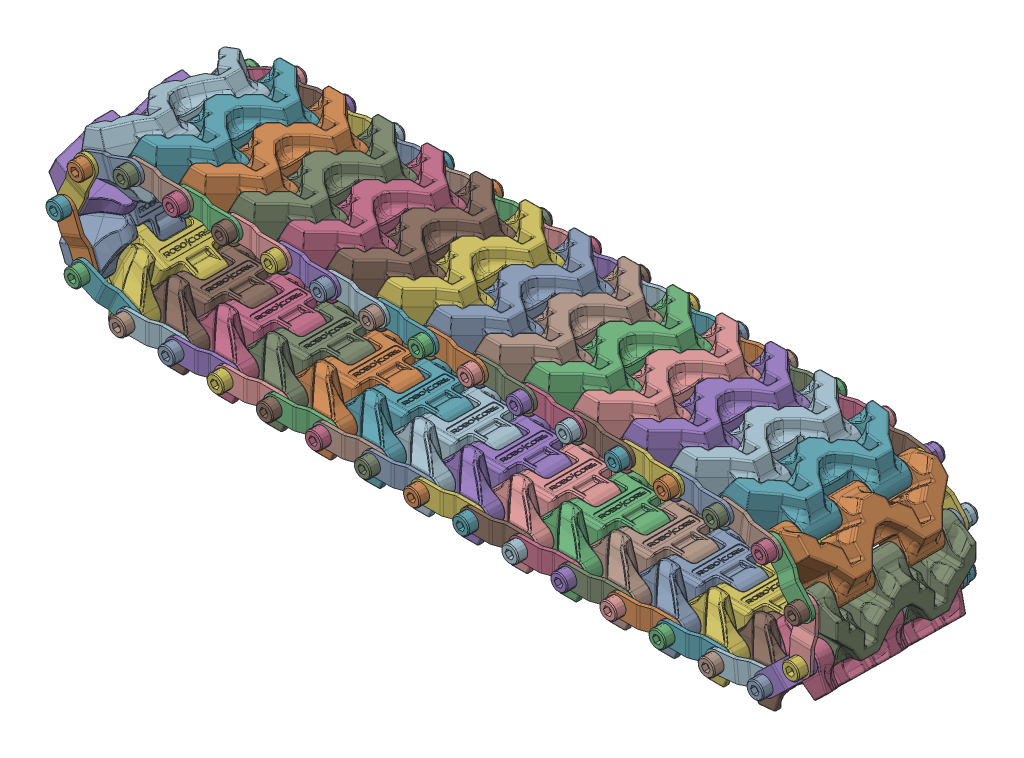
SolidWorks assembly FullTread, configuration Default. Lengths in mm.
Overall size (324.74 77.89 74).
198 component instances, 4 part files, 1 mates.
Components (placement in the parent):
- TRAKTOR_Track_Componentes-V2-5: TRAKTOR_Track_Componentes-V2 [Default] at (-2273.6713 -64.6666 0) x (-0.381584 0.924334 0) z (0 0 -1) size (30.08 26.28 74)
  - Esteira-Traktor-ELEMENTO-V2-25: Esteira-Traktor-ELEMENTO-V2 [Default] at (29.9982 -38.3079 0) x (-0.99994 -0.01097 0) z (0 0 -1) size (29.8 25.95 58)
  - Reforco-tirante-Angulado(Valor predeterminado)-37: Reforco-tirante-Angulado(Valor predeterminado) [Default] at (29.9982 -38.3079 -29.7933) x (-0.99994 -0.01097 0) z (0 0 1) size (28.5 8.5 3)
  - socket head cap screw_am(B18.3.1M - 4 x 0.7 x 70 Hex SHCS -- 20NHX)-19: socket head cap screw_am(B18.3.1M - 4 x 0.7 x 70 Hex SHCS -- 20NHX) [Default] at (19.9988 -38.4176 -35.9962) x (0 0 1) z (-0.823084 0.56792 0) size (74 7 7)
  - prevailing torque nut thin insert_din(DIN EN ISO 10511 - M4 - N)-6: prevailing torque nut thin insert_din(DIN EN ISO 10511 - M4 - N) [Default] at (19.9988 -38.4176 33.9462) x (0.987369 -0.158435 0) z (0 0 1) size (7 8.08 5)
  - Reforco-tirante-Angulado(Valor predeterminado)-51: Reforco-tirante-Angulado(Valor predeterminado) [Default] at (29.9982 -38.3079 31.2029) x (0.99994 0.01097 0) z (0 0 1) size (28.5 8.5 3)
- TRAKTOR_Track_Componentes-V2-61: TRAKTOR_Track_Componentes-V2 [Default] at (-2264.8931 -41.7825 0) x (-0.916884 0.399154 0) z (0 0 -1) size (30.08 26.28 74)
  - Esteira-Traktor-ELEMENTO-V2-25: Esteira-Traktor-ELEMENTO-V2 [Default] at (29.9982 -38.3079 0) x (-0.99994 -0.01097 0) z (0 0 -1) size (29.8 25.95 58)
  - Reforco-tirante-Angulado(Valor predeterminado)-37: Reforco-tirante-Angulado(Valor predeterminado) [Default] at (29.9982 -38.3079 -29.7933) x (-0.99994 -0.01097 0) z (0 0 1) size (28.5 8.5 3)
  - socket head cap screw_am(B18.3.1M - 4 x 0.7 x 70 Hex SHCS -- 20NHX)-19: socket head cap screw_am(B18.3.1M - 4 x 0.7 x 70 Hex SHCS -- 20NHX) [Default] at (19.9988 -38.4176 -35.9962) x (0 0 1) z (-0.823084 0.56792 0) size (74 7 7)
  - prevailing torque nut thin insert_din(DIN EN ISO 10511 - M4 - N)-6: prevailing torque nut thin insert_din(DIN EN ISO 10511 - M4 - N) [Default] at (19.9988 -38.4176 33.9462) x (0.987369 -0.158435 0) z (0 0 1) size (7 8.08 5)
  - Reforco-tirante-Angulado(Valor predeterminado)-51: Reforco-tirante-Angulado(Valor predeterminado) [Default] at (29.9982 -38.3079 31.2029) x (0.99994 0.01097 0) z (0 0 1) size (28.5 8.5 3)
- TRAKTOR_Track_Componentes-V2-62: TRAKTOR_Track_Componentes-V2 [Default] at (-2258.9524 -30.4263 0) x (-0.99995 -0.010047 0) z (0 0 -1) size (30.08 26.28 74)
  - Esteira-Traktor-ELEMENTO-V2-25: Esteira-Traktor-ELEMENTO-V2 [Default] at (29.9982 -38.3079 0) x (-0.99994 -0.01097 0) z (0 0 -1) size (29.8 25.95 58)
  - Reforco-tirante-Angulado(Valor predeterminado)-37: Reforco-tirante-Angulado(Valor predeterminado) [Default] at (29.9982 -38.3079 -29.7933) x (-0.99994 -0.01097 0) z (0 0 1) size (28.5 8.5 3)
  - socket head cap screw_am(B18.3.1M - 4 x 0.7 x 70 Hex SHCS -- 20NHX)-19: socket head cap screw_am(B18.3.1M - 4 x 0.7 x 70 Hex SHCS -- 20NHX) [Default] at (19.9988 -38.4176 -35.9962) x (0 0 1) z (-0.823084 0.56792 0) size (74 7 7)
  - prevailing torque nut thin insert_din(DIN EN ISO 10511 - M4 - N)-6: prevailing torque nut thin insert_din(DIN EN ISO 10511 - M4 - N) [Default] at (19.9988 -38.4176 33.9462) x (0.987369 -0.158435 0) z (0 0 1) size (7 8.08 5)
  - Reforco-tirante-Angulado(Valor predeterminado)-51: Reforco-tirante-Angulado(Valor predeterminado) [Default] at (29.9982 -38.3079 31.2029) x (0.99994 0.01097 0) z (0 0 1) size (28.5 8.5 3)
- TRAKTOR_Track_Componentes-V2-63: TRAKTOR_Track_Componentes-V2 [Default] at (-2238.9881 -30.4082 0) x (-0.99994 -0.01097 0) z (0 0 -1) size (30.08 26.28 74)
  - Esteira-Traktor-ELEMENTO-V2-25: Esteira-Traktor-ELEMENTO-V2 [Default] at (29.9982 -38.3079 0) x (-0.99994 -0.01097 0) z (0 0 -1) size (29.8 25.95 58)
  - Reforco-tirante-Angulado(Valor predeterminado)-37: Reforco-tirante-Angulado(Valor predeterminado) [Default] at (29.9982 -38.3079 -29.7933) x (-0.99994 -0.01097 0) z (0 0 1) size (28.5 8.5 3)
  - socket head cap screw_am(B18.3.1M - 4 x 0.7 x 70 Hex SHCS -- 20NHX)-19: socket head cap screw_am(B18.3.1M - 4 x 0.7 x 70 Hex SHCS -- 20NHX) [Default] at (19.9988 -38.4176 -35.9962) x (0 0 1) z (-0.823084 0.56792 0) size (74 7 7)
  - prevailing torque nut thin insert_din(DIN EN ISO 10511 - M4 - N)-6: prevailing torque nut thin insert_din(DIN EN ISO 10511 - M4 - N) [Default] at (19.9988 -38.4176 33.9462) x (0.987369 -0.158435 0) z (0 0 1) size (7 8.08 5)
  - Reforco-tirante-Angulado(Valor predeterminado)-51: Reforco-tirante-Angulado(Valor predeterminado) [Default] at (29.9982 -38.3079 31.2029) x (0.99994 0.01097 0) z (0 0 1) size (28.5 8.5 3)
- TRAKTOR_Track_Componentes-V2-64: TRAKTOR_Track_Componentes-V2 [Default] at (-2218.9881 -30.4082 0) x (-0.99994 -0.01097 0) z (0 0 -1) size (30.08 26.28 74)
  - Esteira-Traktor-ELEMENTO-V2-25: Esteira-Traktor-ELEMENTO-V2 [Default] at (29.9982 -38.3079 0) x (-0.99994 -0.01097 0) z (0 0 -1) size (29.8 25.95 58)
  - Reforco-tirante-Angulado(Valor predeterminado)-37: Reforco-tirante-Angulado(Valor predeterminado) [Default] at (29.9982 -38.3079 -29.7933) x (-0.99994 -0.01097 0) z (0 0 1) size (28.5 8.5 3)
  - socket head cap screw_am(B18.3.1M - 4 x 0.7 x 70 Hex SHCS -- 20NHX)-19: socket head cap screw_am(B18.3.1M - 4 x 0.7 x 70 Hex SHCS -- 20NHX) [Default] at (19.9988 -38.4176 -35.9962) x (0 0 1) z (-0.823084 0.56792 0) size (74 7 7)
  - prevailing torque nut thin insert_din(DIN EN ISO 10511 - M4 - N)-6: prevailing torque nut thin insert_din(DIN EN ISO 10511 - M4 - N) [Default] at (19.9988 -38.4176 33.9462) x (0.987369 -0.158435 0) z (0 0 1) size (7 8.08 5)
  - Reforco-tirante-Angulado(Valor predeterminado)-51: Reforco-tirante-Angulado(Valor predeterminado) [Default] at (29.9982 -38.3079 31.2029) x (0.99994 0.01097 0) z (0 0 1) size (28.5 8.5 3)
- TRAKTOR_Track_Componentes-V2-65: TRAKTOR_Track_Componentes-V2 [Default] at (-2198.9881 -30.4082 0) x (-0.99994 -0.01097 0) z (0 0 -1) size (30.08 26.28 74)
  - Esteira-Traktor-ELEMENTO-V2-25: Esteira-Traktor-ELEMENTO-V2 [Default] at (29.9982 -38.3079 0) x (-0.99994 -0.01097 0) z (0 0 -1) size (29.8 25.95 58)
  - Reforco-tirante-Angulado(Valor predeterminado)-37: Reforco-tirante-Angulado(Valor predeterminado) [Default] at (29.9982 -38.3079 -29.7933) x (-0.99994 -0.01097 0) z (0 0 1) size (28.5 8.5 3)
  - socket head cap screw_am(B18.3.1M - 4 x 0.7 x 70 Hex SHCS -- 20NHX)-19: socket head cap screw_am(B18.3.1M - 4 x 0.7 x 70 Hex SHCS -- 20NHX) [Default] at (19.9988 -38.4176 -35.9962) x (0 0 1) z (-0.823084 0.56792 0) size (74 7 7)
  - prevailing torque nut thin insert_din(DIN EN ISO 10511 - M4 - N)-6: prevailing torque nut thin insert_din(DIN EN ISO 10511 - M4 - N) [Default] at (19.9988 -38.4176 33.9462) x (0.987369 -0.158435 0) z (0 0 1) size (7 8.08 5)
  - Reforco-tirante-Angulado(Valor predeterminado)-51: Reforco-tirante-Angulado(Valor predeterminado) [Default] at (29.9982 -38.3079 31.2029) x (0.99994 0.01097 0) z (0 0 1) size (28.5 8.5 3)
- TRAKTOR_Track_Componentes-V2-66: TRAKTOR_Track_Componentes-V2 [Default] at (-2178.9881 -30.4082 0) x (-0.99994 -0.01097 0) z (0 0 -1) size (30.08 26.28 74)
  - Esteira-Traktor-ELEMENTO-V2-25: Esteira-Traktor-ELEMENTO-V2 [Default] at (29.9982 -38.3079 0) x (-0.99994 -0.01097 0) z (0 0 -1) size (29.8 25.95 58)
  - Reforco-tirante-Angulado(Valor predeterminado)-37: Reforco-tirante-Angulado(Valor predeterminado) [Default] at (29.9982 -38.3079 -29.7933) x (-0.99994 -0.01097 0) z (0 0 1) size (28.5 8.5 3)
  - socket head cap screw_am(B18.3.1M - 4 x 0.7 x 70 Hex SHCS -- 20NHX)-19: socket head cap screw_am(B18.3.1M - 4 x 0.7 x 70 Hex SHCS -- 20NHX) [Default] at (19.9988 -38.4176 -35.9962) x (0 0 1) z (-0.823084 0.56792 0) size (74 7 7)
  - prevailing torque nut thin insert_din(DIN EN ISO 10511 - M4 - N)-6: prevailing torque nut thin insert_din(DIN EN ISO 10511 - M4 - N) [Default] at (19.9988 -38.4176 33.9462) x (0.987369 -0.158435 0) z (0 0 1) size (7 8.08 5)
  - Reforco-tirante-Angulado(Valor predeterminado)-51: Reforco-tirante-Angulado(Valor predeterminado) [Default] at (29.9982 -38.3079 31.2029) x (0.99994 0.01097 0) z (0 0 1) size (28.5 8.5 3)
- TRAKTOR_Track_Componentes-V2-67: TRAKTOR_Track_Componentes-V2 [Default] at (-2158.9881 -30.4082 0) x (-0.99994 -0.01097 0) z (0 0 -1) size (30.08 26.28 74)
  - Esteira-Traktor-ELEMENTO-V2-25: Esteira-Traktor-ELEMENTO-V2 [Default] at (29.9982 -38.3079 0) x (-0.99994 -0.01097 0) z (0 0 -1) size (29.8 25.95 58)
  - Reforco-tirante-Angulado(Valor predeterminado)-37: Reforco-tirante-Angulado(Valor predeterminado) [Default] at (29.9982 -38.3079 -29.7933) x (-0.99994 -0.01097 0) z (0 0 1) size (28.5 8.5 3)
  - socket head cap screw_am(B18.3.1M - 4 x 0.7 x 70 Hex SHCS -- 20NHX)-19: socket head cap screw_am(B18.3.1M - 4 x 0.7 x 70 Hex SHCS -- 20NHX) [Default] at (19.9988 -38.4176 -35.9962) x (0 0 1) z (-0.823084 0.56792 0) size (74 7 7)
  - prevailing torque nut thin insert_din(DIN EN ISO 10511 - M4 - N)-6: prevailing torque nut thin insert_din(DIN EN ISO 10511 - M4 - N) [Default] at (19.9988 -38.4176 33.9462) x (0.987369 -0.158435 0) z (0 0 1) size (7 8.08 5)
  - Reforco-tirante-Angulado(Valor predeterminado)-51: Reforco-tirante-Angulado(Valor predeterminado) [Default] at (29.9982 -38.3079 31.2029) x (0.99994 0.01097 0) z (0 0 1) size (28.5 8.5 3)
- TRAKTOR_Track_Componentes-V2-68: TRAKTOR_Track_Componentes-V2 [Default] at (-2138.9881 -30.4082 0) x (-0.99994 -0.01097 0) z (0 0 -1) size (30.08 26.28 74)
  - Esteira-Traktor-ELEMENTO-V2-25: Esteira-Traktor-ELEMENTO-V2 [Default] at (29.9982 -38.3079 0) x (-0.99994 -0.01097 0) z (0 0 -1) size (29.8 25.95 58)
  - Reforco-tirante-Angulado(Valor predeterminado)-37: Reforco-tirante-Angulado(Valor predeterminado) [Default] at (29.9982 -38.3079 -29.7933) x (-0.99994 -0.01097 0) z (0 0 1) size (28.5 8.5 3)
  - socket head cap screw_am(B18.3.1M - 4 x 0.7 x 70 Hex SHCS -- 20NHX)-19: socket head cap screw_am(B18.3.1M - 4 x 0.7 x 70 Hex SHCS -- 20NHX) [Default] at (19.9988 -38.4176 -35.9962) x (0 0 1) z (-0.823084 0.56792 0) size (74 7 7)
  - prevailing torque nut thin insert_din(DIN EN ISO 10511 - M4 - N)-6: prevailing torque nut thin insert_din(DIN EN ISO 10511 - M4 - N) [Default] at (19.9988 -38.4176 33.9462) x (0.987369 -0.158435 0) z (0 0 1) size (7 8.08 5)
  - Reforco-tirante-Angulado(Valor predeterminado)-51: Reforco-tirante-Angulado(Valor predeterminado) [Default] at (29.9982 -38.3079 31.2029) x (0.99994 0.01097 0) z (0 0 1) size (28.5 8.5 3)
- TRAKTOR_Track_Componentes-V2-69: TRAKTOR_Track_Componentes-V2 [Default] at (-2118.9881 -30.4082 0) x (-0.99994 -0.01097 0) z (0 0 -1) size (30.08 26.28 74)
  - Esteira-Traktor-ELEMENTO-V2-25: Esteira-Traktor-ELEMENTO-V2 [Default] at (29.9982 -38.3079 0) x (-0.99994 -0.01097 0) z (0 0 -1) size (29.8 25.95 58)
  - Reforco-tirante-Angulado(Valor predeterminado)-37: Reforco-tirante-Angulado(Valor predeterminado) [Default] at (29.9982 -38.3079 -29.7933) x (-0.99994 -0.01097 0) z (0 0 1) size (28.5 8.5 3)
  - socket head cap screw_am(B18.3.1M - 4 x 0.7 x 70 Hex SHCS -- 20NHX)-19: socket head cap screw_am(B18.3.1M - 4 x 0.7 x 70 Hex SHCS -- 20NHX) [Default] at (19.9988 -38.4176 -35.9962) x (0 0 1) z (-0.823084 0.56792 0) size (74 7 7)
  - prevailing torque nut thin insert_din(DIN EN ISO 10511 - M4 - N)-6: prevailing torque nut thin insert_din(DIN EN ISO 10511 - M4 - N) [Default] at (19.9988 -38.4176 33.9462) x (0.987369 -0.158435 0) z (0 0 1) size (7 8.08 5)
  - Reforco-tirante-Angulado(Valor predeterminado)-51: Reforco-tirante-Angulado(Valor predeterminado) [Default] at (29.9982 -38.3079 31.2029) x (0.99994 0.01097 0) z (0 0 1) size (28.5 8.5 3)
- TRAKTOR_Track_Componentes-V2-70: TRAKTOR_Track_Componentes-V2 [Default] at (-2098.9881 -30.4082 0) x (-0.99994 -0.01097 0) z (0 0 -1) size (30.08 26.28 74)
  - Esteira-Traktor-ELEMENTO-V2-25: Esteira-Traktor-ELEMENTO-V2 [Default] at (29.9982 -38.3079 0) x (-0.99994 -0.01097 0) z (0 0 -1) size (29.8 25.95 58)
  - Reforco-tirante-Angulado(Valor predeterminado)-37: Reforco-tirante-Angulado(Valor predeterminado) [Default] at (29.9982 -38.3079 -29.7933) x (-0.99994 -0.01097 0) z (0 0 1) size (28.5 8.5 3)
  - socket head cap screw_am(B18.3.1M - 4 x 0.7 x 70 Hex SHCS -- 20NHX)-19: socket head cap screw_am(B18.3.1M - 4 x 0.7 x 70 Hex SHCS -- 20NHX) [Default] at (19.9988 -38.4176 -35.9962) x (0 0 1) z (-0.823084 0.56792 0) size (74 7 7)
  - prevailing torque nut thin insert_din(DIN EN ISO 10511 - M4 - N)-6: prevailing torque nut thin insert_din(DIN EN ISO 10511 - M4 - N) [Default] at (19.9988 -38.4176 33.9462) x (0.987369 -0.158435 0) z (0 0 1) size (7 8.08 5)
  - Reforco-tirante-Angulado(Valor predeterminado)-51: Reforco-tirante-Angulado(Valor predeterminado) [Default] at (29.9982 -38.3079 31.2029) x (0.99994 0.01097 0) z (0 0 1) size (28.5 8.5 3)
- TRAKTOR_Track_Componentes-V2-71: TRAKTOR_Track_Componentes-V2 [Default] at (-2078.9881 -30.4082 0) x (-0.99994 -0.01097 0) z (0 0 -1) size (30.08 26.28 74)
  - Esteira-Traktor-ELEMENTO-V2-25: Esteira-Traktor-ELEMENTO-V2 [Default] at (29.9982 -38.3079 0) x (-0.99994 -0.01097 0) z (0 0 -1) size (29.8 25.95 58)
  - Reforco-tirante-Angulado(Valor predeterminado)-37: Reforco-tirante-Angulado(Valor predeterminado) [Default] at (29.9982 -38.3079 -29.7933) x (-0.99994 -0.01097 0) z (0 0 1) size (28.5 8.5 3)
  - socket head cap screw_am(B18.3.1M - 4 x 0.7 x 70 Hex SHCS -- 20NHX)-19: socket head cap screw_am(B18.3.1M - 4 x 0.7 x 70 Hex SHCS -- 20NHX) [Default] at (19.9988 -38.4176 -35.9962) x (0 0 1) z (-0.823084 0.56792 0) size (74 7 7)
  - prevailing torque nut thin insert_din(DIN EN ISO 10511 - M4 - N)-6: prevailing torque nut thin insert_din(DIN EN ISO 10511 - M4 - N) [Default] at (19.9988 -38.4176 33.9462) x (0.987369 -0.158435 0) z (0 0 1) size (7 8.08 5)
  - Reforco-tirante-Angulado(Valor predeterminado)-51: Reforco-tirante-Angulado(Valor predeterminado) [Default] at (29.9982 -38.3079 31.2029) x (0.99994 0.01097 0) z (0 0 1) size (28.5 8.5 3)
- TRAKTOR_Track_Componentes-V2-72: TRAKTOR_Track_Componentes-V2 [Default] at (-2058.9881 -30.4082 0) x (-0.99994 -0.01097 0) z (0 0 -1) size (30.08 26.28 74)
  - Esteira-Traktor-ELEMENTO-V2-25: Esteira-Traktor-ELEMENTO-V2 [Default] at (29.9982 -38.3079 0) x (-0.99994 -0.01097 0) z (0 0 -1) size (29.8 25.95 58)
  - Reforco-tirante-Angulado(Valor predeterminado)-37: Reforco-tirante-Angulado(Valor predeterminado) [Default] at (29.9982 -38.3079 -29.7933) x (-0.99994 -0.01097 0) z (0 0 1) size (28.5 8.5 3)
  - socket head cap screw_am(B18.3.1M - 4 x 0.7 x 70 Hex SHCS -- 20NHX)-19: socket head cap screw_am(B18.3.1M - 4 x 0.7 x 70 Hex SHCS -- 20NHX) [Default] at (19.9988 -38.4176 -35.9962) x (0 0 1) z (-0.823084 0.56792 0) size (74 7 7)
  - prevailing torque nut thin insert_din(DIN EN ISO 10511 - M4 - N)-6: prevailing torque nut thin insert_din(DIN EN ISO 10511 - M4 - N) [Default] at (19.9988 -38.4176 33.9462) x (0.987369 -0.158435 0) z (0 0 1) size (7 8.08 5)
  - Reforco-tirante-Angulado(Valor predeterminado)-51: Reforco-tirante-Angulado(Valor predeterminado) [Default] at (29.9982 -38.3079 31.2029) x (0.99994 0.01097 0) z (0 0 1) size (28.5 8.5 3)
- TRAKTOR_Track_Componentes-V2-73: TRAKTOR_Track_Componentes-V2 [Default] at (-2038.9881 -30.4082 0) x (-0.99994 -0.01097 0) z (0 0 -1) size (30.08 26.28 74)
  - Esteira-Traktor-ELEMENTO-V2-25: Esteira-Traktor-ELEMENTO-V2 [Default] at (29.9982 -38.3079 0) x (-0.99994 -0.01097 0) z (0 0 -1) size (29.8 25.95 58)
  - Reforco-tirante-Angulado(Valor predeterminado)-37: Reforco-tirante-Angulado(Valor predeterminado) [Default] at (29.9982 -38.3079 -29.7933) x (-0.99994 -0.01097 0) z (0 0 1) size (28.5 8.5 3)
  - socket head cap screw_am(B18.3.1M - 4 x 0.7 x 70 Hex SHCS -- 20NHX)-19: socket head cap screw_am(B18.3.1M - 4 x 0.7 x 70 Hex SHCS -- 20NHX) [Default] at (19.9988 -38.4176 -35.9962) x (0 0 1) z (-0.823084 0.56792 0) size (74 7 7)
  - prevailing torque nut thin insert_din(DIN EN ISO 10511 - M4 - N)-6: prevailing torque nut thin insert_din(DIN EN ISO 10511 - M4 - N) [Default] at (19.9988 -38.4176 33.9462) x (0.987369 -0.158435 0) z (0 0 1) size (7 8.08 5)
  - Reforco-tirante-Angulado(Valor predeterminado)-51: Reforco-tirante-Angulado(Valor predeterminado) [Default] at (29.9982 -38.3079 31.2029) x (0.99994 0.01097 0) z (0 0 1) size (28.5 8.5 3)
- TRAKTOR_Track_Componentes-V2-74: TRAKTOR_Track_Componentes-V2 [Default] at (-2022.9285 -26.7462 0) x (-0.994144 -0.108059 0) z (0 0 -1) size (30.08 26.28 74)
  - Esteira-Traktor-ELEMENTO-V2-25: Esteira-Traktor-ELEMENTO-V2 [Default] at (29.9982 -38.3079 0) x (-0.99994 -0.01097 0) z (0 0 -1) size (29.8 25.95 58)
  - Reforco-tirante-Angulado(Valor predeterminado)-37: Reforco-tirante-Angulado(Valor predeterminado) [Default] at (29.9982 -38.3079 -29.7933) x (-0.99994 -0.01097 0) z (0 0 1) size (28.5 8.5 3)
  - socket head cap screw_am(B18.3.1M - 4 x 0.7 x 70 Hex SHCS -- 20NHX)-19: socket head cap screw_am(B18.3.1M - 4 x 0.7 x 70 Hex SHCS -- 20NHX) [Default] at (19.9988 -38.4176 -35.9962) x (0 0 1) z (-0.823084 0.56792 0) size (74 7 7)
  - prevailing torque nut thin insert_din(DIN EN ISO 10511 - M4 - N)-6: prevailing torque nut thin insert_din(DIN EN ISO 10511 - M4 - N) [Default] at (19.9988 -38.4176 33.9462) x (0.987369 -0.158435 0) z (0 0 1) size (7 8.08 5)
  - Reforco-tirante-Angulado(Valor predeterminado)-51: Reforco-tirante-Angulado(Valor predeterminado) [Default] at (29.9982 -38.3079 31.2029) x (0.99994 0.01097 0) z (0 0 1) size (28.5 8.5 3)
- TRAKTOR_Track_Componentes-V2-75: TRAKTOR_Track_Componentes-V2 [Default] at (-2037.0538 -11.8158 0) x (-0.711348 -0.70284 0) z (0 0 -1) size (30.08 26.28 74)
  - Esteira-Traktor-ELEMENTO-V2-25: Esteira-Traktor-ELEMENTO-V2 [Default] at (29.9982 -38.3079 0) x (-0.99994 -0.01097 0) z (0 0 -1) size (29.8 25.95 58)
  - Reforco-tirante-Angulado(Valor predeterminado)-37: Reforco-tirante-Angulado(Valor predeterminado) [Default] at (29.9982 -38.3079 -29.7933) x (-0.99994 -0.01097 0) z (0 0 1) size (28.5 8.5 3)
  - socket head cap screw_am(B18.3.1M - 4 x 0.7 x 70 Hex SHCS -- 20NHX)-19: socket head cap screw_am(B18.3.1M - 4 x 0.7 x 70 Hex SHCS -- 20NHX) [Default] at (19.9988 -38.4176 -35.9962) x (0 0 1) z (-0.823084 0.56792 0) size (74 7 7)
  - prevailing torque nut thin insert_din(DIN EN ISO 10511 - M4 - N)-6: prevailing torque nut thin insert_din(DIN EN ISO 10511 - M4 - N) [Default] at (19.9988 -38.4176 33.9462) x (0.987369 -0.158435 0) z (0 0 1) size (7 8.08 5)
  - Reforco-tirante-Angulado(Valor predeterminado)-51: Reforco-tirante-Angulado(Valor predeterminado) [Default] at (29.9982 -38.3079 31.2029) x (0.99994 0.01097 0) z (0 0 1) size (28.5 8.5 3)
- TRAKTOR_Track_Componentes-V2-76: TRAKTOR_Track_Componentes-V2 [Default] at (-2061.5581 -12.3449 0) x (-0.02272 -0.999742 0) z (0 0 -1) size (30.08 26.28 74)
  - Esteira-Traktor-ELEMENTO-V2-25: Esteira-Traktor-ELEMENTO-V2 [Default] at (29.9982 -38.3079 0) x (-0.99994 -0.01097 0) z (0 0 -1) size (29.8 25.95 58)
  - Reforco-tirante-Angulado(Valor predeterminado)-37: Reforco-tirante-Angulado(Valor predeterminado) [Default] at (29.9982 -38.3079 -29.7933) x (-0.99994 -0.01097 0) z (0 0 1) size (28.5 8.5 3)
  - socket head cap screw_am(B18.3.1M - 4 x 0.7 x 70 Hex SHCS -- 20NHX)-19: socket head cap screw_am(B18.3.1M - 4 x 0.7 x 70 Hex SHCS -- 20NHX) [Default] at (19.9988 -38.4176 -35.9962) x (0 0 1) z (-0.823084 0.56792 0) size (74 7 7)
  - prevailing torque nut thin insert_din(DIN EN ISO 10511 - M4 - N)-6: prevailing torque nut thin insert_din(DIN EN ISO 10511 - M4 - N) [Default] at (19.9988 -38.4176 33.9462) x (0.987369 -0.158435 0) z (0 0 1) size (7 8.08 5)
  - Reforco-tirante-Angulado(Valor predeterminado)-51: Reforco-tirante-Angulado(Valor predeterminado) [Default] at (29.9982 -38.3079 31.2029) x (0.99994 0.01097 0) z (0 0 1) size (28.5 8.5 3)
- TRAKTOR_Track_Componentes-V2-77: TRAKTOR_Track_Componentes-V2 [Default] at (-2078.8044 -29.7606 0) x (0.678685 -0.734429 0) z (0 0 -1) size (30.08 26.28 74)
  - Esteira-Traktor-ELEMENTO-V2-25: Esteira-Traktor-ELEMENTO-V2 [Default] at (29.9982 -38.3079 0) x (-0.99994 -0.01097 0) z (0 0 -1) size (29.8 25.95 58)
  - Reforco-tirante-Angulado(Valor predeterminado)-37: Reforco-tirante-Angulado(Valor predeterminado) [Default] at (29.9982 -38.3079 -29.7933) x (-0.99994 -0.01097 0) z (0 0 1) size (28.5 8.5 3)
  - socket head cap screw_am(B18.3.1M - 4 x 0.7 x 70 Hex SHCS -- 20NHX)-19: socket head cap screw_am(B18.3.1M - 4 x 0.7 x 70 Hex SHCS -- 20NHX) [Default] at (19.9988 -38.4176 -35.9962) x (0 0 1) z (-0.823084 0.56792 0) size (74 7 7)
  - prevailing torque nut thin insert_din(DIN EN ISO 10511 - M4 - N)-6: prevailing torque nut thin insert_din(DIN EN ISO 10511 - M4 - N) [Default] at (19.9988 -38.4176 33.9462) x (0.987369 -0.158435 0) z (0 0 1) size (7 8.08 5)
  - Reforco-tirante-Angulado(Valor predeterminado)-51: Reforco-tirante-Angulado(Valor predeterminado) [Default] at (29.9982 -38.3079 31.2029) x (0.99994 0.01097 0) z (0 0 1) size (28.5 8.5 3)
- TRAKTOR_Track_Componentes-V2-78: TRAKTOR_Track_Componentes-V2 [Default] at (-2081.3993 -51.376 0) x (0.992442 -0.122716 0) z (0 0 -1) size (30.08 26.28 74)
  - Esteira-Traktor-ELEMENTO-V2-25: Esteira-Traktor-ELEMENTO-V2 [Default] at (29.9982 -38.3079 0) x (-0.99994 -0.01097 0) z (0 0 -1) size (29.8 25.95 58)
  - Reforco-tirante-Angulado(Valor predeterminado)-37: Reforco-tirante-Angulado(Valor predeterminado) [Default] at (29.9982 -38.3079 -29.7933) x (-0.99994 -0.01097 0) z (0 0 1) size (28.5 8.5 3)
  - socket head cap screw_am(B18.3.1M - 4 x 0.7 x 70 Hex SHCS -- 20NHX)-19: socket head cap screw_am(B18.3.1M - 4 x 0.7 x 70 Hex SHCS -- 20NHX) [Default] at (19.9988 -38.4176 -35.9962) x (0 0 1) z (-0.823084 0.56792 0) size (74 7 7)
  - prevailing torque nut thin insert_din(DIN EN ISO 10511 - M4 - N)-6: prevailing torque nut thin insert_din(DIN EN ISO 10511 - M4 - N) [Default] at (19.9988 -38.4176 33.9462) x (0.987369 -0.158435 0) z (0 0 1) size (7 8.08 5)
  - Reforco-tirante-Angulado(Valor predeterminado)-51: Reforco-tirante-Angulado(Valor predeterminado) [Default] at (29.9982 -38.3079 31.2029) x (0.99994 0.01097 0) z (0 0 1) size (28.5 8.5 3)
- TRAKTOR_Track_Componentes-V2-79: TRAKTOR_Track_Componentes-V2 [Default] at (-2096.4134 -54.3376 0) x (0.99994 0.01097 0) z (0 0 -1) size (30.08 26.28 74)
  - Esteira-Traktor-ELEMENTO-V2-25: Esteira-Traktor-ELEMENTO-V2 [Default] at (29.9982 -38.3079 0) x (-0.99994 -0.01097 0) z (0 0 -1) size (29.8 25.95 58)
  - Reforco-tirante-Angulado(Valor predeterminado)-37: Reforco-tirante-Angulado(Valor predeterminado) [Default] at (29.9982 -38.3079 -29.7933) x (-0.99994 -0.01097 0) z (0 0 1) size (28.5 8.5 3)
  - socket head cap screw_am(B18.3.1M - 4 x 0.7 x 70 Hex SHCS -- 20NHX)-19: socket head cap screw_am(B18.3.1M - 4 x 0.7 x 70 Hex SHCS -- 20NHX) [Default] at (19.9988 -38.4176 -35.9962) x (0 0 1) z (-0.823084 0.56792 0) size (74 7 7)
  - prevailing torque nut thin insert_din(DIN EN ISO 10511 - M4 - N)-6: prevailing torque nut thin insert_din(DIN EN ISO 10511 - M4 - N) [Default] at (19.9988 -38.4176 33.9462) x (0.987369 -0.158435 0) z (0 0 1) size (7 8.08 5)
  - Reforco-tirante-Angulado(Valor predeterminado)-51: Reforco-tirante-Angulado(Valor predeterminado) [Default] at (29.9982 -38.3079 31.2029) x (0.99994 0.01097 0) z (0 0 1) size (28.5 8.5 3)
- TRAKTOR_Track_Componentes-V2-80: TRAKTOR_Track_Componentes-V2 [Default] at (-2116.4134 -54.3376 0) x (0.99994 0.01097 0) z (0 0 -1) size (30.08 26.28 74)
  - Esteira-Traktor-ELEMENTO-V2-25: Esteira-Traktor-ELEMENTO-V2 [Default] at (29.9982 -38.3079 0) x (-0.99994 -0.01097 0) z (0 0 -1) size (29.8 25.95 58)
  - Reforco-tirante-Angulado(Valor predeterminado)-37: Reforco-tirante-Angulado(Valor predeterminado) [Default] at (29.9982 -38.3079 -29.7933) x (-0.99994 -0.01097 0) z (0 0 1) size (28.5 8.5 3)
  - socket head cap screw_am(B18.3.1M - 4 x 0.7 x 70 Hex SHCS -- 20NHX)-19: socket head cap screw_am(B18.3.1M - 4 x 0.7 x 70 Hex SHCS -- 20NHX) [Default] at (19.9988 -38.4176 -35.9962) x (0 0 1) z (-0.823084 0.56792 0) size (74 7 7)
  - prevailing torque nut thin insert_din(DIN EN ISO 10511 - M4 - N)-6: prevailing torque nut thin insert_din(DIN EN ISO 10511 - M4 - N) [Default] at (19.9988 -38.4176 33.9462) x (0.987369 -0.158435 0) z (0 0 1) size (7 8.08 5)
  - Reforco-tirante-Angulado(Valor predeterminado)-51: Reforco-tirante-Angulado(Valor predeterminado) [Default] at (29.9982 -38.3079 31.2029) x (0.99994 0.01097 0) z (0 0 1) size (28.5 8.5 3)
- TRAKTOR_Track_Componentes-V2-81: TRAKTOR_Track_Componentes-V2 [Default] at (-2136.4134 -54.3376 0) x (0.99994 0.01097 0) z (0 0 -1) size (30.08 26.28 74)
  - Esteira-Traktor-ELEMENTO-V2-25: Esteira-Traktor-ELEMENTO-V2 [Default] at (29.9982 -38.3079 0) x (-0.99994 -0.01097 0) z (0 0 -1) size (29.8 25.95 58)
  - Reforco-tirante-Angulado(Valor predeterminado)-37: Reforco-tirante-Angulado(Valor predeterminado) [Default] at (29.9982 -38.3079 -29.7933) x (-0.99994 -0.01097 0) z (0 0 1) size (28.5 8.5 3)
  - socket head cap screw_am(B18.3.1M - 4 x 0.7 x 70 Hex SHCS -- 20NHX)-19: socket head cap screw_am(B18.3.1M - 4 x 0.7 x 70 Hex SHCS -- 20NHX) [Default] at (19.9988 -38.4176 -35.9962) x (0 0 1) z (-0.823084 0.56792 0) size (74 7 7)
  - prevailing torque nut thin insert_din(DIN EN ISO 10511 - M4 - N)-6: prevailing torque nut thin insert_din(DIN EN ISO 10511 - M4 - N) [Default] at (19.9988 -38.4176 33.9462) x (0.987369 -0.158435 0) z (0 0 1) size (7 8.08 5)
  - Reforco-tirante-Angulado(Valor predeterminado)-51: Reforco-tirante-Angulado(Valor predeterminado) [Default] at (29.9982 -38.3079 31.2029) x (0.99994 0.01097 0) z (0 0 1) size (28.5 8.5 3)
- TRAKTOR_Track_Componentes-V2-82: TRAKTOR_Track_Componentes-V2 [Default] at (-2156.4134 -54.3376 0) x (0.99994 0.01097 0) z (0 0 -1) size (30.08 26.28 74)
  - Esteira-Traktor-ELEMENTO-V2-25: Esteira-Traktor-ELEMENTO-V2 [Default] at (29.9982 -38.3079 0) x (-0.99994 -0.01097 0) z (0 0 -1) size (29.8 25.95 58)
  - Reforco-tirante-Angulado(Valor predeterminado)-37: Reforco-tirante-Angulado(Valor predeterminado) [Default] at (29.9982 -38.3079 -29.7933) x (-0.99994 -0.01097 0) z (0 0 1) size (28.5 8.5 3)
  - socket head cap screw_am(B18.3.1M - 4 x 0.7 x 70 Hex SHCS -- 20NHX)-19: socket head cap screw_am(B18.3.1M - 4 x 0.7 x 70 Hex SHCS -- 20NHX) [Default] at (19.9988 -38.4176 -35.9962) x (0 0 1) z (-0.823084 0.56792 0) size (74 7 7)
  - prevailing torque nut thin insert_din(DIN EN ISO 10511 - M4 - N)-6: prevailing torque nut thin insert_din(DIN EN ISO 10511 - M4 - N) [Default] at (19.9988 -38.4176 33.9462) x (0.987369 -0.158435 0) z (0 0 1) size (7 8.08 5)
  - Reforco-tirante-Angulado(Valor predeterminado)-51: Reforco-tirante-Angulado(Valor predeterminado) [Default] at (29.9982 -38.3079 31.2029) x (0.99994 0.01097 0) z (0 0 1) size (28.5 8.5 3)
- TRAKTOR_Track_Componentes-V2-83: TRAKTOR_Track_Componentes-V2 [Default] at (-2176.4134 -54.3376 0) x (0.99994 0.01097 0) z (0 0 -1) size (30.08 26.28 74)
  - Esteira-Traktor-ELEMENTO-V2-25: Esteira-Traktor-ELEMENTO-V2 [Default] at (29.9982 -38.3079 0) x (-0.99994 -0.01097 0) z (0 0 -1) size (29.8 25.95 58)
  - Reforco-tirante-Angulado(Valor predeterminado)-37: Reforco-tirante-Angulado(Valor predeterminado) [Default] at (29.9982 -38.3079 -29.7933) x (-0.99994 -0.01097 0) z (0 0 1) size (28.5 8.5 3)
  - socket head cap screw_am(B18.3.1M - 4 x 0.7 x 70 Hex SHCS -- 20NHX)-19: socket head cap screw_am(B18.3.1M - 4 x 0.7 x 70 Hex SHCS -- 20NHX) [Default] at (19.9988 -38.4176 -35.9962) x (0 0 1) z (-0.823084 0.56792 0) size (74 7 7)
  - prevailing torque nut thin insert_din(DIN EN ISO 10511 - M4 - N)-6: prevailing torque nut thin insert_din(DIN EN ISO 10511 - M4 - N) [Default] at (19.9988 -38.4176 33.9462) x (0.987369 -0.158435 0) z (0 0 1) size (7 8.08 5)
  - Reforco-tirante-Angulado(Valor predeterminado)-51: Reforco-tirante-Angulado(Valor predeterminado) [Default] at (29.9982 -38.3079 31.2029) x (0.99994 0.01097 0) z (0 0 1) size (28.5 8.5 3)
- TRAKTOR_Track_Componentes-V2-84: TRAKTOR_Track_Componentes-V2 [Default] at (-2196.4134 -54.3376 0) x (0.99994 0.01097 0) z (0 0 -1) size (30.08 26.28 74)
  - Esteira-Traktor-ELEMENTO-V2-25: Esteira-Traktor-ELEMENTO-V2 [Default] at (29.9982 -38.3079 0) x (-0.99994 -0.01097 0) z (0 0 -1) size (29.8 25.95 58)
  - Reforco-tirante-Angulado(Valor predeterminado)-37: Reforco-tirante-Angulado(Valor predeterminado) [Default] at (29.9982 -38.3079 -29.7933) x (-0.99994 -0.01097 0) z (0 0 1) size (28.5 8.5 3)
  - socket head cap screw_am(B18.3.1M - 4 x 0.7 x 70 Hex SHCS -- 20NHX)-19: socket head cap screw_am(B18.3.1M - 4 x 0.7 x 70 Hex SHCS -- 20NHX) [Default] at (19.9988 -38.4176 -35.9962) x (0 0 1) z (-0.823084 0.56792 0) size (74 7 7)
  - prevailing torque nut thin insert_din(DIN EN ISO 10511 - M4 - N)-6: prevailing torque nut thin insert_din(DIN EN ISO 10511 - M4 - N) [Default] at (19.9988 -38.4176 33.9462) x (0.987369 -0.158435 0) z (0 0 1) size (7 8.08 5)
  - Reforco-tirante-Angulado(Valor predeterminado)-51: Reforco-tirante-Angulado(Valor predeterminado) [Default] at (29.9982 -38.3079 31.2029) x (0.99994 0.01097 0) z (0 0 1) size (28.5 8.5 3)
- TRAKTOR_Track_Componentes-V2-85: TRAKTOR_Track_Componentes-V2 [Default] at (-2216.4134 -54.3376 0) x (0.99994 0.01097 0) z (0 0 -1) size (30.08 26.28 74)
  - Esteira-Traktor-ELEMENTO-V2-25: Esteira-Traktor-ELEMENTO-V2 [Default] at (29.9982 -38.3079 0) x (-0.99994 -0.01097 0) z (0 0 -1) size (29.8 25.95 58)
  - Reforco-tirante-Angulado(Valor predeterminado)-37: Reforco-tirante-Angulado(Valor predeterminado) [Default] at (29.9982 -38.3079 -29.7933) x (-0.99994 -0.01097 0) z (0 0 1) size (28.5 8.5 3)
  - socket head cap screw_am(B18.3.1M - 4 x 0.7 x 70 Hex SHCS -- 20NHX)-19: socket head cap screw_am(B18.3.1M - 4 x 0.7 x 70 Hex SHCS -- 20NHX) [Default] at (19.9988 -38.4176 -35.9962) x (0 0 1) z (-0.823084 0.56792 0) size (74 7 7)
  - prevailing torque nut thin insert_din(DIN EN ISO 10511 - M4 - N)-6: prevailing torque nut thin insert_din(DIN EN ISO 10511 - M4 - N) [Default] at (19.9988 -38.4176 33.9462) x (0.987369 -0.158435 0) z (0 0 1) size (7 8.08 5)
  - Reforco-tirante-Angulado(Valor predeterminado)-51: Reforco-tirante-Angulado(Valor predeterminado) [Default] at (29.9982 -38.3079 31.2029) x (0.99994 0.01097 0) z (0 0 1) size (28.5 8.5 3)
- TRAKTOR_Track_Componentes-V2-111: TRAKTOR_Track_Componentes-V2 [Default] at (-2236.4134 -54.3376 0) x (0.99994 0.01097 0) z (0 0 -1) size (30.08 26.28 74)
  - Esteira-Traktor-ELEMENTO-V2-25: Esteira-Traktor-ELEMENTO-V2 [Default] at (29.9982 -38.3079 0) x (-0.99994 -0.01097 0) z (0 0 -1) size (29.8 25.95 58)
  - Reforco-tirante-Angulado(Valor predeterminado)-37: Reforco-tirante-Angulado(Valor predeterminado) [Default] at (29.9982 -38.3079 -29.7933) x (-0.99994 -0.01097 0) z (0 0 1) size (28.5 8.5 3)
  - socket head cap screw_am(B18.3.1M - 4 x 0.7 x 70 Hex SHCS -- 20NHX)-19: socket head cap screw_am(B18.3.1M - 4 x 0.7 x 70 Hex SHCS -- 20NHX) [Default] at (19.9988 -38.4176 -35.9962) x (0 0 1) z (-0.823084 0.56792 0) size (74 7 7)
  - prevailing torque nut thin insert_din(DIN EN ISO 10511 - M4 - N)-6: prevailing torque nut thin insert_din(DIN EN ISO 10511 - M4 - N) [Default] at (19.9988 -38.4176 33.9462) x (0.987369 -0.158435 0) z (0 0 1) size (7 8.08 5)
  - Reforco-tirante-Angulado(Valor predeterminado)-51: Reforco-tirante-Angulado(Valor predeterminado) [Default] at (29.9982 -38.3079 31.2029) x (0.99994 0.01097 0) z (0 0 1) size (28.5 8.5 3)
- TRAKTOR_Track_Componentes-V2-112: TRAKTOR_Track_Componentes-V2 [Default] at (-2256.4134 -54.3376 0) x (0.99994 0.01097 0) z (0 0 -1) size (30.08 26.28 74)
  - Esteira-Traktor-ELEMENTO-V2-25: Esteira-Traktor-ELEMENTO-V2 [Default] at (29.9982 -38.3079 0) x (-0.99994 -0.01097 0) z (0 0 -1) size (29.8 25.95 58)
  - Reforco-tirante-Angulado(Valor predeterminado)-37: Reforco-tirante-Angulado(Valor predeterminado) [Default] at (29.9982 -38.3079 -29.7933) x (-0.99994 -0.01097 0) z (0 0 1) size (28.5 8.5 3)
  - socket head cap screw_am(B18.3.1M - 4 x 0.7 x 70 Hex SHCS -- 20NHX)-19: socket head cap screw_am(B18.3.1M - 4 x 0.7 x 70 Hex SHCS -- 20NHX) [Default] at (19.9988 -38.4176 -35.9962) x (0 0 1) z (-0.823084 0.56792 0) size (74 7 7)
  - prevailing torque nut thin insert_din(DIN EN ISO 10511 - M4 - N)-6: prevailing torque nut thin insert_din(DIN EN ISO 10511 - M4 - N) [Default] at (19.9988 -38.4176 33.9462) x (0.987369 -0.158435 0) z (0 0 1) size (7 8.08 5)
  - Reforco-tirante-Angulado(Valor predeterminado)-51: Reforco-tirante-Angulado(Valor predeterminado) [Default] at (29.9982 -38.3079 31.2029) x (0.99994 0.01097 0) z (0 0 1) size (28.5 8.5 3)
- TRAKTOR_Track_Componentes-V2-113: TRAKTOR_Track_Componentes-V2 [Default] at (-2276.4134 -54.3376 0) x (0.99994 0.01097 0) z (0 0 -1) size (30.08 26.28 74)
  - Esteira-Traktor-ELEMENTO-V2-25: Esteira-Traktor-ELEMENTO-V2 [Default] at (29.9982 -38.3079 0) x (-0.99994 -0.01097 0) z (0 0 -1) size (29.8 25.95 58)
  - Reforco-tirante-Angulado(Valor predeterminado)-37: Reforco-tirante-Angulado(Valor predeterminado) [Default] at (29.9982 -38.3079 -29.7933) x (-0.99994 -0.01097 0) z (0 0 1) size (28.5 8.5 3)
  - socket head cap screw_am(B18.3.1M - 4 x 0.7 x 70 Hex SHCS -- 20NHX)-19: socket head cap screw_am(B18.3.1M - 4 x 0.7 x 70 Hex SHCS -- 20NHX) [Default] at (19.9988 -38.4176 -35.9962) x (0 0 1) z (-0.823084 0.56792 0) size (74 7 7)
  - prevailing torque nut thin insert_din(DIN EN ISO 10511 - M4 - N)-6: prevailing torque nut thin insert_din(DIN EN ISO 10511 - M4 - N) [Default] at (19.9988 -38.4176 33.9462) x (0.987369 -0.158435 0) z (0 0 1) size (7 8.08 5)
  - Reforco-tirante-Angulado(Valor predeterminado)-51: Reforco-tirante-Angulado(Valor predeterminado) [Default] at (29.9982 -38.3079 31.2029) x (0.99994 0.01097 0) z (0 0 1) size (28.5 8.5 3)
- TRAKTOR_Track_Componentes-V2-114: TRAKTOR_Track_Componentes-V2 [Default] at (-2296.4134 -54.3376 0) x (0.99994 0.01097 0) z (0 0 -1) size (30.08 26.28 74)
  - Esteira-Traktor-ELEMENTO-V2-25: Esteira-Traktor-ELEMENTO-V2 [Default] at (29.9982 -38.3079 0) x (-0.99994 -0.01097 0) z (0 0 -1) size (29.8 25.95 58)
  - Reforco-tirante-Angulado(Valor predeterminado)-37: Reforco-tirante-Angulado(Valor predeterminado) [Default] at (29.9982 -38.3079 -29.7933) x (-0.99994 -0.01097 0) z (0 0 1) size (28.5 8.5 3)
  - socket head cap screw_am(B18.3.1M - 4 x 0.7 x 70 Hex SHCS -- 20NHX)-19: socket head cap screw_am(B18.3.1M - 4 x 0.7 x 70 Hex SHCS -- 20NHX) [Default] at (19.9988 -38.4176 -35.9962) x (0 0 1) z (-0.823084 0.56792 0) size (74 7 7)
  - prevailing torque nut thin insert_din(DIN EN ISO 10511 - M4 - N)-6: prevailing torque nut thin insert_din(DIN EN ISO 10511 - M4 - N) [Default] at (19.9988 -38.4176 33.9462) x (0.987369 -0.158435 0) z (0 0 1) size (7 8.08 5)
  - Reforco-tirante-Angulado(Valor predeterminado)-51: Reforco-tirante-Angulado(Valor predeterminado) [Default] at (29.9982 -38.3079 31.2029) x (0.99994 0.01097 0) z (0 0 1) size (28.5 8.5 3)
- TRAKTOR_Track_Componentes-V2-115: TRAKTOR_Track_Componentes-V2 [Default] at (-2316.4134 -54.3376 0) x (0.99994 0.01097 0) z (0 0 -1) size (30.08 26.28 74)
  - Esteira-Traktor-ELEMENTO-V2-25: Esteira-Traktor-ELEMENTO-V2 [Default] at (29.9982 -38.3079 0) x (-0.99994 -0.01097 0) z (0 0 -1) size (29.8 25.95 58)
  - Reforco-tirante-Angulado(Valor predeterminado)-37: Reforco-tirante-Angulado(Valor predeterminado) [Default] at (29.9982 -38.3079 -29.7933) x (-0.99994 -0.01097 0) z (0 0 1) size (28.5 8.5 3)
  - socket head cap screw_am(B18.3.1M - 4 x 0.7 x 70 Hex SHCS -- 20NHX)-19: socket head cap screw_am(B18.3.1M - 4 x 0.7 x 70 Hex SHCS -- 20NHX) [Default] at (19.9988 -38.4176 -35.9962) x (0 0 1) z (-0.823084 0.56792 0) size (74 7 7)
  - prevailing torque nut thin insert_din(DIN EN ISO 10511 - M4 - N)-6: prevailing torque nut thin insert_din(DIN EN ISO 10511 - M4 - N) [Default] at (19.9988 -38.4176 33.9462) x (0.987369 -0.158435 0) z (0 0 1) size (7 8.08 5)
  - Reforco-tirante-Angulado(Valor predeterminado)-51: Reforco-tirante-Angulado(Valor predeterminado) [Default] at (29.9982 -38.3079 31.2029) x (0.99994 0.01097 0) z (0 0 1) size (28.5 8.5 3)
- TRAKTOR_Track_Componentes-V2-116: TRAKTOR_Track_Componentes-V2 [Default] at (-2320.4065 -65.7369 0) x (0.932986 0.359912 0) z (0 0 -1) size (30.08 26.28 74)
  - Esteira-Traktor-ELEMENTO-V2-25: Esteira-Traktor-ELEMENTO-V2 [Default] at (29.9982 -38.3079 0) x (-0.99994 -0.01097 0) z (0 0 -1) size (29.8 25.95 58)
  - Reforco-tirante-Angulado(Valor predeterminado)-37: Reforco-tirante-Angulado(Valor predeterminado) [Default] at (29.9982 -38.3079 -29.7933) x (-0.99994 -0.01097 0) z (0 0 1) size (28.5 8.5 3)
  - socket head cap screw_am(B18.3.1M - 4 x 0.7 x 70 Hex SHCS -- 20NHX)-19: socket head cap screw_am(B18.3.1M - 4 x 0.7 x 70 Hex SHCS -- 20NHX) [Default] at (19.9988 -38.4176 -35.9962) x (0 0 1) z (-0.823084 0.56792 0) size (74 7 7)
  - prevailing torque nut thin insert_din(DIN EN ISO 10511 - M4 - N)-6: prevailing torque nut thin insert_din(DIN EN ISO 10511 - M4 - N) [Default] at (19.9988 -38.4176 33.9462) x (0.987369 -0.158435 0) z (0 0 1) size (7 8.08 5)
  - Reforco-tirante-Angulado(Valor predeterminado)-51: Reforco-tirante-Angulado(Valor predeterminado) [Default] at (29.9982 -38.3079 31.2029) x (0.99994 0.01097 0) z (0 0 1) size (28.5 8.5 3)
- TRAKTOR_Track_Componentes-V2-117: TRAKTOR_Track_Componentes-V2 [Default] at (-2297.762 -75.0564 0) x (0.420936 0.907091 0) z (0 0 -1) size (30.08 26.28 74)
  - Esteira-Traktor-ELEMENTO-V2-25: Esteira-Traktor-ELEMENTO-V2 [Default] at (29.9982 -38.3079 0) x (-0.99994 -0.01097 0) z (0 0 -1) size (29.8 25.95 58)
  - Reforco-tirante-Angulado(Valor predeterminado)-37: Reforco-tirante-Angulado(Valor predeterminado) [Default] at (29.9982 -38.3079 -29.7933) x (-0.99994 -0.01097 0) z (0 0 1) size (28.5 8.5 3)
  - socket head cap screw_am(B18.3.1M - 4 x 0.7 x 70 Hex SHCS -- 20NHX)-19: socket head cap screw_am(B18.3.1M - 4 x 0.7 x 70 Hex SHCS -- 20NHX) [Default] at (19.9988 -38.4176 -35.9962) x (0 0 1) z (-0.823084 0.56792 0) size (74 7 7)
  - prevailing torque nut thin insert_din(DIN EN ISO 10511 - M4 - N)-6: prevailing torque nut thin insert_din(DIN EN ISO 10511 - M4 - N) [Default] at (19.9988 -38.4176 33.9462) x (0.987369 -0.158435 0) z (0 0 1) size (7 8.08 5)
  - Reforco-tirante-Angulado(Valor predeterminado)-51: Reforco-tirante-Angulado(Valor predeterminado) [Default] at (29.9982 -38.3079 31.2029) x (0.99994 0.01097 0) z (0 0 1) size (28.5 8.5 3)
Mates (geometry in assembly coordinates):
- Coincident15: coincident: cylinder of TRAKTOR_Track_Componentes-V2-5/Esteira-Traktor-ELEMENTO-V2-25 through (-3570.6522 8.3878 29) axis (0 0 -1) radius 2
